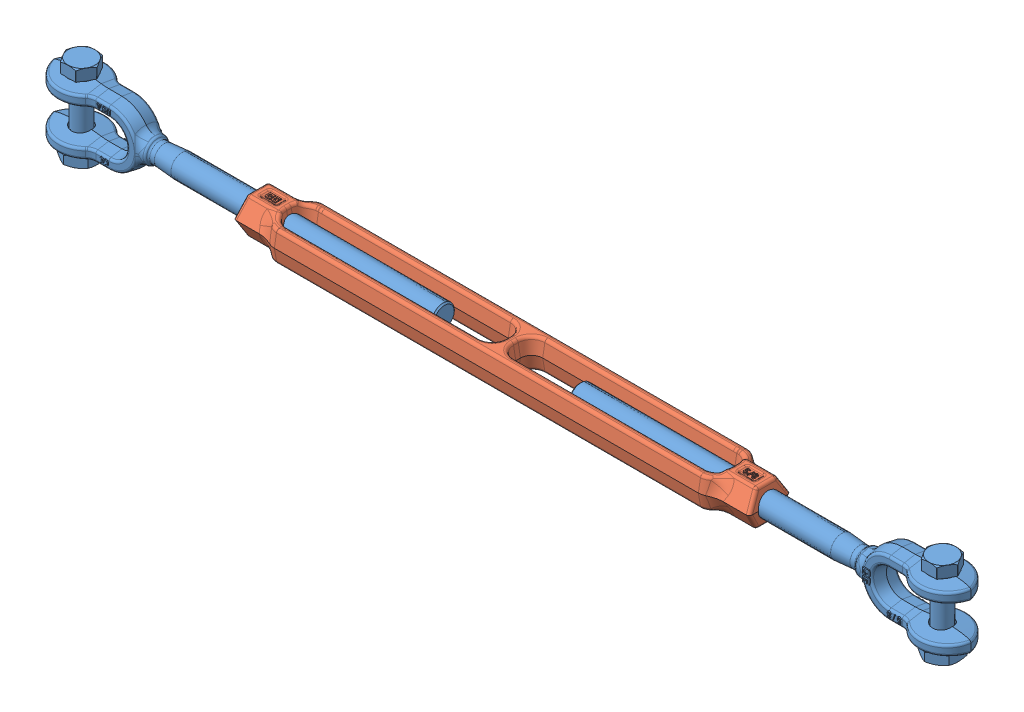
SolidWorks assembly 000008-07_REVA_TURNBUCKLE, JAW & JAW_0.625 X 12, configuration Default. Lengths in mm.
Overall size (650.46 62.19 38.13).
3 component instances, 2 part files, 7 mates.
Components (placement in the parent):
- CROSBY_HB-4037_JAW_0.625 X 12-1: CROSBY_HB-4037_JAW_0.625 X 12 [Default] at origin size (277.35 62.19 33.45)
- CROSBY HG-2510_BODY_0.625 X 12-1: CROSBY HG-2510_BODY_0.625 X 12 [Default] at (-304.8 0 0) x (1 0 0) z (0 1 0) size (365.25 38.13 30.73)
- CROSBY_HB-4037_JAW_0.625 X 12-3: CROSBY_HB-4037_JAW_0.625 X 12 [Default] at (-609.6 0 -0.0001) x (-1 0 0) z (0 0 -1) size (277.35 62.19 33.45)
Mates (geometry in assembly coordinates):
- Coincident1: coincident aligned: plane of CROSBY_HB-4037_JAW_0.625 X 12-1 through (0 0 0) normal (0 1 0); plane of assembly through (0 0 0) normal (0 1 0)
- Coincident2: coincident aligned: plane of CROSBY_HB-4037_JAW_0.625 X 12-1 through (0 0 0) normal (0 0 1); plane of assembly through (0 0 0) normal (0 0 1)
- Coincident3: coincident aligned: plane of CROSBY_HB-4037_JAW_0.625 X 12-1 through (0 0 0) normal (1 0 0); plane of assembly through (0 0 0) normal (1 0 0)
- Concentric1: concentric anti-aligned: cylinder of CROSBY_HB-4037_JAW_0.625 X 12-1 through (-48.6275 0 0) axis (-1 0 0) radius 8.001; cylinder of CROSBY HG-2510_BODY_0.625 X 12-1 through (-156.718 0 0) axis (1 0 0) radius 6.731
- Parallel1: parallel aligned: plane of CROSBY_HB-4037_JAW_0.625 X 12-1 through (0 0 0) normal (0 1 0); plane of assembly through (0 0 0) normal (0 1 0)
- Parallel2: parallel aligned: plane of CROSBY HG-2510_BODY_0.625 X 12-1 through (-304.8 0 0) normal (0 1 0); plane of assembly through (0 0 0) normal (0 1 0)
- Distance1: distance = 304.8 mm aligned: plane of CROSBY HG-2510_BODY_0.625 X 12-1; plane of assembly through (0 0 0) normal (1 0 0)
